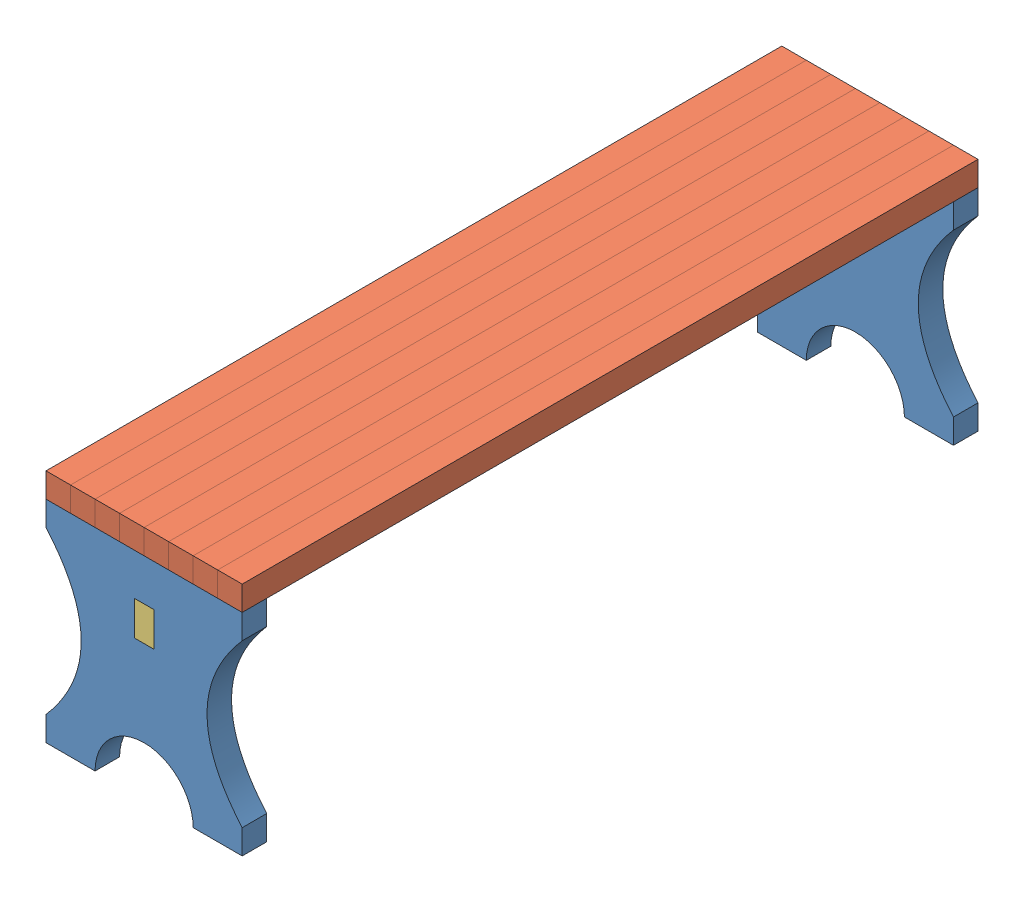
SolidWorks assembly Сборка2, configuration По умолчанию. Lengths in mm.
Overall size (400 480 1500).
11 component instances, 3 part files, 52 mates.
Components (placement in the parent):
- Ножка_Деталь_Версия_2.1-1: Ножка_Деталь_Версия_2.1 [По умолчанию] at (-115.7087 -475 15.3417) size (400 460 50)
- Деталь_Сиденье_Версия_2.0-1: Деталь_Сиденье_Версия_2.0 [По умолчанию] at (-165.7087 -235 765.3417) x (0 0 -1) z (-1 0 0) size (1500 50 50)
- Деталь_Сиденье_Версия_2.0-2: Деталь_Сиденье_Версия_2.0 [По умолчанию] at (-165.7087 -235 765.3417) x (0 0 1) z (1 0 0) size (1500 50 50)
- Деталь_Сиденье_Версия_2.0-3: Деталь_Сиденье_Версия_2.0 [По умолчанию] at (34.2913 -235 765.3417) x (0 0 1) z (1 0 0) size (1500 50 50)
- Деталь_Сиденье_Версия_2.0-4: Деталь_Сиденье_Версия_2.0 [По умолчанию] at (-15.7087 -235 765.3417) x (0 0 1) z (1 0 0) size (1500 50 50)
- Деталь_Сиденье_Версия_2.0-5: Деталь_Сиденье_Версия_2.0 [По умолчанию] at (-65.7087 -235 765.3417) x (0 0 1) z (1 0 0) size (1500 50 50)
- Деталь_Сиденье_Версия_2.0-6: Деталь_Сиденье_Версия_2.0 [По умолчанию] at (-65.7087 -235 765.3417) x (0 0 -1) z (-1 0 0) size (1500 50 50)
- Деталь_Сиденье_Версия_2.0-7: Деталь_Сиденье_Версия_2.0 [По умолчанию] at (-215.7087 -235 765.3417) x (0 0 -1) z (-1 0 0) size (1500 50 50)
- Ножка_Деталь_Версия_2.1-2: Ножка_Деталь_Версия_2.1 [По умолчанию] at (-115.7087 -475 1465.3417) size (400 460 50)
- Деталь_Сиденье_Версия_2.0-9: Деталь_Сиденье_Версия_2.0 [По умолчанию] at (-315.7087 -235 765.3417) x (0 0 1) z (1 0 0) size (1500 50 50)
- Соединительная_балка_Деталь-1: Соединительная_балка_Деталь [По умолчанию] at (-135.7087 -380 765.3417) x (0 0 -1) z (1 0 0) size (1500 70 40)
Mates (geometry in assembly coordinates):
- Совпадение59: coincident anti-aligned: plane of Ножка_Деталь_Версия_2.1-2 through (-305.7087 -230 1505.3417) normal (0 0 1); plane of Деталь_Сиденье_Версия_2.0-9 through (-305.7087 -230 1505.3417) normal (0 0 -1)
- Совпадение60: coincident anti-aligned: plane of Ножка_Деталь_Версия_2.1-2 through (-305.7087 -230 1475.3417) normal (0 0 -1); plane of Деталь_Сиденье_Версия_2.0-9 through (-305.7087 -230 1475.3417) normal (0 0 1)
- Совпадение61: coincident anti-aligned: plane of Ножка_Деталь_Версия_2.1-2 through (-275.7087 -230 1475.3417) normal (1 0 0); plane of Деталь_Сиденье_Версия_2.0-9 through (-275.7087 -230 1475.3417) normal (-1 0 0)
- Совпадение62: coincident anti-aligned: plane of Ножка_Деталь_Версия_2.1-2 through (-305.7087 -230 1475.3417) normal (-1 0 0); plane of Деталь_Сиденье_Версия_2.0-9 through (-305.7087 -230 1475.3417) normal (1 0 0)
- Совпадение63: coincident anti-aligned: plane of Ножка_Деталь_Версия_2.1-2 through (-115.7087 -230 1465.3417) normal (0 1 0); plane of Деталь_Сиденье_Версия_2.0-9 through (-315.7087 -230 765.3417) normal (0 -1 0)
- Совпадение64: coincident anti-aligned: plane of Деталь_Сиденье_Версия_2.0-7 through (-225.7087 -230 1505.3417) normal (0 0 -1); plane of Ножка_Деталь_Версия_2.1-2 through (-255.7087 -230 1505.3417) normal (0 0 1)
- Совпадение65: coincident anti-aligned: plane of Деталь_Сиденье_Версия_2.0-7 through (-225.7087 -230 1475.3417) normal (0 0 1); plane of Ножка_Деталь_Версия_2.1-2 through (-255.7087 -230 1475.3417) normal (0 0 -1)
- Совпадение66: coincident anti-aligned: plane of Деталь_Сиденье_Версия_2.0-7 through (-225.7087 -230 1505.3417) normal (-1 0 0); plane of Ножка_Деталь_Версия_2.1-2 through (-225.7087 -230 1475.3417) normal (1 0 0)
- Совпадение67: coincident anti-aligned: plane of Деталь_Сиденье_Версия_2.0-7 through (-255.7087 -230 1505.3417) normal (1 0 0); plane of Ножка_Деталь_Версия_2.1-2 through (-255.7087 -230 1475.3417) normal (-1 0 0)
- Совпадение68: coincident anti-aligned: plane of Деталь_Сиденье_Версия_2.0-7 through (-215.7087 -230 765.3417) normal (0 -1 0); plane of Ножка_Деталь_Версия_2.1-2 through (-115.7087 -230 1465.3417) normal (0 1 0)
- Совпадение69: coincident anti-aligned: plane of Деталь_Сиденье_Версия_2.0-1 through (-175.7087 -230 1505.3417) normal (0 0 -1); plane of Ножка_Деталь_Версия_2.1-2 through (-205.7087 -230 1505.3417) normal (0 0 1)
- Совпадение70: coincident anti-aligned: plane of Деталь_Сиденье_Версия_2.0-1 through (-175.7087 -230 1475.3417) normal (0 0 1); plane of Ножка_Деталь_Версия_2.1-2 through (-205.7087 -230 1475.3417) normal (0 0 -1)
- Совпадение71: coincident anti-aligned: plane of Деталь_Сиденье_Версия_2.0-1 through (-205.7087 -230 1505.3417) normal (1 0 0); plane of Ножка_Деталь_Версия_2.1-2 through (-205.7087 -230 1475.3417) normal (-1 0 0)
- Совпадение72: coincident anti-aligned: plane of Деталь_Сиденье_Версия_2.0-1 through (-175.7087 -230 1505.3417) normal (-1 0 0); plane of Ножка_Деталь_Версия_2.1-2 through (-175.7087 -230 1475.3417) normal (1 0 0)
- Совпадение73: coincident anti-aligned: plane of Деталь_Сиденье_Версия_2.0-1 through (-165.7087 -230 765.3417) normal (0 -1 0); plane of Ножка_Деталь_Версия_2.1-2 through (-115.7087 -230 1465.3417) normal (0 1 0)
- Совпадение74: coincident anti-aligned: plane of Деталь_Сиденье_Версия_2.0-2 through (-155.7087 -230 1505.3417) normal (0 0 -1); plane of Ножка_Деталь_Версия_2.1-2 through (-155.7087 -230 1505.3417) normal (0 0 1)
- Совпадение75: coincident anti-aligned: plane of Деталь_Сиденье_Версия_2.0-2 through (-155.7087 -230 1475.3417) normal (1 0 0); plane of Ножка_Деталь_Версия_2.1-2 through (-155.7087 -230 1475.3417) normal (-1 0 0)
- Совпадение76: coincident anti-aligned: plane of Деталь_Сиденье_Версия_2.0-2 through (-155.7087 -230 1475.3417) normal (0 0 1); plane of Ножка_Деталь_Версия_2.1-2 through (-155.7087 -230 1475.3417) normal (0 0 -1)
- Совпадение77: coincident anti-aligned: plane of Деталь_Сиденье_Версия_2.0-2 through (-125.7087 -230 1475.3417) normal (-1 0 0); plane of Ножка_Деталь_Версия_2.1-2 through (-125.7087 -230 1475.3417) normal (1 0 0)
- Совпадение78: coincident anti-aligned: plane of Деталь_Сиденье_Версия_2.0-2 through (-155.7087 -230 1475.3417) normal (1 0 0); plane of Ножка_Деталь_Версия_2.1-2 through (-155.7087 -230 1475.3417) normal (-1 0 0)
- Совпадение79: coincident anti-aligned: plane of Деталь_Сиденье_Версия_2.0-2 through (-165.7087 -230 765.3417) normal (0 -1 0); plane of Ножка_Деталь_Версия_2.1-2 through (-115.7087 -230 1465.3417) normal (0 1 0)
- Совпадение80: coincident anti-aligned: plane of Деталь_Сиденье_Версия_2.0-6 through (-75.7087 -230 1505.3417) normal (0 0 -1); plane of Ножка_Деталь_Версия_2.1-2 through (-105.7087 -230 1505.3417) normal (0 0 1)
- Совпадение81: coincident anti-aligned: plane of Деталь_Сиденье_Версия_2.0-6 through (-105.7087 -230 1505.3417) normal (1 0 0); plane of Ножка_Деталь_Версия_2.1-2 through (-105.7087 -230 1475.3417) normal (-1 0 0)
- Совпадение82: coincident anti-aligned: plane of Деталь_Сиденье_Версия_2.0-6 through (-75.7087 -230 1505.3417) normal (-1 0 0); plane of Ножка_Деталь_Версия_2.1-2 through (-75.7087 -230 1475.3417) normal (1 0 0)
- Совпадение83: coincident anti-aligned: plane of Деталь_Сиденье_Версия_2.0-6 through (-75.7087 -230 1475.3417) normal (0 0 1); plane of Ножка_Деталь_Версия_2.1-2 through (-105.7087 -230 1475.3417) normal (0 0 -1)
- Совпадение84: coincident anti-aligned: plane of Деталь_Сиденье_Версия_2.0-6 through (-65.7087 -230 765.3417) normal (0 -1 0); plane of Ножка_Деталь_Версия_2.1-2 through (-115.7087 -230 1465.3417) normal (0 1 0)
- Совпадение85: coincident anti-aligned: plane of Деталь_Сиденье_Версия_2.0-5 through (-55.7087 -230 1505.3417) normal (0 0 -1); plane of Ножка_Деталь_Версия_2.1-2 through (-55.7087 -230 1505.3417) normal (0 0 1)
- Совпадение86: coincident anti-aligned: plane of Деталь_Сиденье_Версия_2.0-5 through (-55.7087 -230 1475.3417) normal (1 0 0); plane of Ножка_Деталь_Версия_2.1-2 through (-55.7087 -230 1475.3417) normal (-1 0 0)
- Совпадение87: coincident anti-aligned: plane of Деталь_Сиденье_Версия_2.0-5 through (-25.7087 -230 1475.3417) normal (-1 0 0); plane of Ножка_Деталь_Версия_2.1-2 through (-25.7087 -230 1475.3417) normal (1 0 0)
- Совпадение88: coincident anti-aligned: plane of Деталь_Сиденье_Версия_2.0-5 through (-55.7087 -230 1475.3417) normal (0 0 1); plane of Ножка_Деталь_Версия_2.1-2 through (-55.7087 -230 1475.3417) normal (0 0 -1)
- Совпадение89: coincident anti-aligned: plane of Деталь_Сиденье_Версия_2.0-5 through (-65.7087 -230 765.3417) normal (0 -1 0); plane of Ножка_Деталь_Версия_2.1-2 through (-115.7087 -230 1465.3417) normal (0 1 0)
- Совпадение92: coincident anti-aligned: plane of Деталь_Сиденье_Версия_2.0-3 through (44.2913 -230 1505.3417) normal (0 0 -1); plane of Ножка_Деталь_Версия_2.1-2 through (-5.7087 -230 1505.3417) normal (0 0 1)
- Совпадение93: coincident anti-aligned: plane of Деталь_Сиденье_Версия_2.0-3 through (44.2913 -230 1475.3417) normal (1 0 0); plane of Ножка_Деталь_Версия_2.1-2 through (44.2913 -230 1475.3417) normal (-1 0 0)
- Совпадение94: coincident anti-aligned: plane of Деталь_Сиденье_Версия_2.0-3 through (44.2913 -230 1475.3417) normal (0 0 1); plane of Ножка_Деталь_Версия_2.1-2 through (44.2913 -230 1475.3417) normal (0 0 -1)
- Совпадение95: coincident anti-aligned: plane of Деталь_Сиденье_Версия_2.0-3 through (44.2913 -230 1505.3417) normal (0 0 -1); plane of Ножка_Деталь_Версия_2.1-2 through (44.2913 -230 1505.3417) normal (0 0 1)
- Совпадение96: coincident anti-aligned: plane of Деталь_Сиденье_Версия_2.0-3 through (34.2913 -230 765.3417) normal (0 -1 0); plane of Ножка_Деталь_Версия_2.1-2 through (-115.7087 -230 1465.3417) normal (0 1 0)
- Совпадение98: coincident anti-aligned: plane of Деталь_Сиденье_Версия_2.0-4 through (-5.7087 -230 1505.3417) normal (0 0 -1); plane of Ножка_Деталь_Версия_2.1-2 through (-5.7087 -230 1505.3417) normal (0 0 1)
- Совпадение99: coincident anti-aligned: plane of Деталь_Сиденье_Версия_2.0-4 through (-5.7087 -230 1475.3417) normal (1 0 0); plane of Ножка_Деталь_Версия_2.1-2 through (-5.7087 -230 1475.3417) normal (-1 0 0)
- Совпадение100: coincident anti-aligned: plane of Деталь_Сиденье_Версия_2.0-4 through (24.2913 -230 1475.3417) normal (-1 0 0); plane of Ножка_Деталь_Версия_2.1-2 through (24.2913 -230 1475.3417) normal (1 0 0)
- Совпадение101: coincident anti-aligned: plane of Деталь_Сиденье_Версия_2.0-4 through (-5.7087 -230 1475.3417) normal (0 0 1); plane of Ножка_Деталь_Версия_2.1-2 through (-5.7087 -230 1475.3417) normal (0 0 -1)
- Совпадение102: coincident anti-aligned: plane of Деталь_Сиденье_Версия_2.0-4 through (-15.7087 -230 765.3417) normal (0 -1 0); plane of Ножка_Деталь_Версия_2.1-2 through (-115.7087 -230 1465.3417) normal (0 1 0)
- Совпадение103: coincident anti-aligned: plane of Ножка_Деталь_Версия_2.1-1 through (44.2913 -230 25.3417) normal (0 0 -1); plane of Деталь_Сиденье_Версия_2.0-3 through (44.2913 -230 25.3417) normal (0 0 1)
- Совпадение104: coincident anti-aligned: plane of Ножка_Деталь_Версия_2.1-1 through (74.2913 -230 25.3417) normal (1 0 0); plane of Деталь_Сиденье_Версия_2.0-3 through (74.2913 -230 25.3417) normal (-1 0 0)
- Совпадение105: coincident anti-aligned: plane of Ножка_Деталь_Версия_2.1-1 through (44.2913 -230 55.3417) normal (0 0 1); plane of Деталь_Сиденье_Версия_2.0-3 through (44.2913 -230 55.3417) normal (0 0 -1)
- Совпадение106: coincident anti-aligned: plane of Ножка_Деталь_Версия_2.1-1 through (44.2913 -230 25.3417) normal (-1 0 0); plane of Деталь_Сиденье_Версия_2.0-3 through (44.2913 -230 25.3417) normal (1 0 0)
- Совпадение107: coincident anti-aligned: plane of Ножка_Деталь_Версия_2.1-1 through (-115.7087 -230 15.3417) normal (0 1 0); plane of Деталь_Сиденье_Версия_2.0-3 through (34.2913 -230 765.3417) normal (0 -1 0)
- Совпадение108: coincident anti-aligned: plane of Ножка_Деталь_Версия_2.1-2 through (-135.7087 -345 1515.3417) normal (1 0 0); plane of Соединительная_балка_Деталь-1 through (-135.7087 -380 765.3417) normal (-1 0 0)
- Совпадение109: coincident anti-aligned: plane of Ножка_Деталь_Версия_2.1-2 through (-135.7087 -415 1515.3417) normal (0 1 0); plane of Соединительная_балка_Деталь-1 through (-95.7087 -415 1515.3417) normal (0 -1 0)
- Совпадение110: coincident anti-aligned: plane of Ножка_Деталь_Версия_2.1-2 through (-135.7087 -345 1515.3417) normal (0 -1 0); plane of Соединительная_балка_Деталь-1 through (-95.7087 -345 1515.3417) normal (0 1 0)
- Совпадение111: coincident anti-aligned: plane of Ножка_Деталь_Версия_2.1-2 through (-95.7087 -345 1515.3417) normal (-1 0 0); plane of Соединительная_балка_Деталь-1 through (-95.7087 -380 765.3417) normal (1 0 0)
- Совпадение112: coincident anti-aligned: plane of Ножка_Деталь_Версия_2.1-2 through (-135.7087 -345 1515.3417) normal (1 0 0); plane of Соединительная_балка_Деталь-1 through (-135.7087 -380 765.3417) normal (-1 0 0)
- Совпадение113: coincident aligned: plane of Ножка_Деталь_Версия_2.1-2 through (-244.0377 -475 1515.3417) normal (0 0 1); plane of Соединительная_балка_Деталь-1 through (-95.7087 -345 1515.3417) normal (0 0 1)
